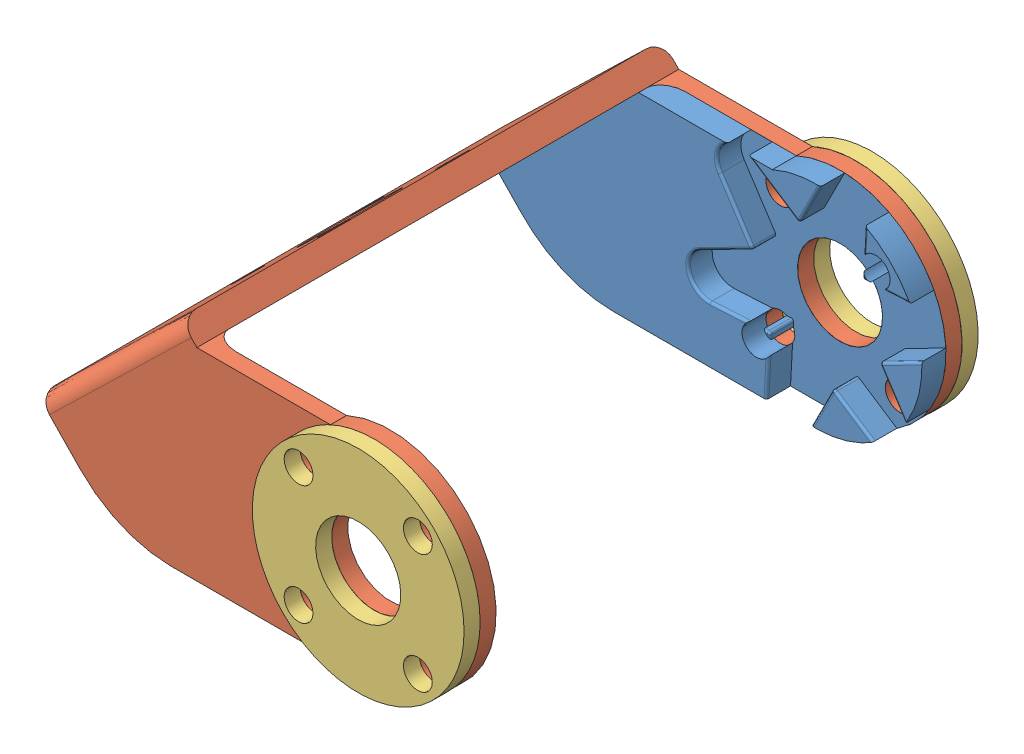
SolidWorks assembly box0_right_supplement, configuration Predeterminado. Lengths in mm.
Overall size (61.37 37.28 64).
5 component instances, 3 part files, 10 mates.
Components (placement in the parent):
- supplement_right_offset_f_horn-1: supplement_right_offset_f_horn [Predeterminado] at (-9.6116 -34.4342 -15.8226) x (0.994321 -0.106425 0) z (-0.106425 -0.994321 0) size (52.15 3.04 29.06)
- box0-1: box0 [Predeterminado] at (-23.9788 -47.6142 42.1774) size (57.24 34.69 60)
  - offset_bracket-1: offset_bracket [Predeterminado] at (1.7542 14.53 -60) x (0.994321 -0.106425 0) z (-0.106425 -0.994321 0) size (54.46 60 29.06)
- suplement_external_bracket-1: suplement_external_bracket [Predeterminado] at (-9.6116 -34.4342 44.1774) x (0.707107 -0.707107 0) z (0.707107 0.707107 0) size (26.36 2 26.36)
- suplement_external_bracket-2: suplement_external_bracket [Predeterminado] at (-9.6116 -34.4342 -17.8226) x (0.707107 0.707107 0) z (-0.707107 0.707107 0) size (26.36 2 26.36)
Mates (geometry in assembly coordinates):
- Coincidente1: coincident: plane of supplement_right_offset_f_horn-1 through (-9.6116 -34.4342 -15.8226) normal (0 0 -1); line of box0-1/offset_bracket-1 through (-15.0626 -22.4342 -15.8226) axis (-1 0 0)
- Coincidente2: coincident anti-aligned: plane of supplement_right_offset_f_horn-1 through (-9.6116 -34.4342 -15.8226) normal (0 0 -1); plane of box0-1/offset_bracket-1 through (-34.8376 -31.7342 -15.8226) normal (0 0 1)
- Coincidente3: coincident anti-aligned: circle of supplement_right_offset_f_horn-1; cylinder of box0-1/offset_bracket-1 through (-9.6116 -34.4342 -15.8226) axis (0 0 -1) radius 5.3
- Coincidente4: coincident aligned: plane of box0-1/offset_bracket-1 through (-34.8376 -47.6142 -15.8226) normal (0 -1 0); plane of supplement_right_offset_f_horn-1 through (-9.6116 -47.6142 -12.8226) normal (0 -1 0)
- Concéntrica1: concentric: cylinder of box0-1/offset_bracket-1 through (-9.6116 -34.4342 40.1774) axis (0 0 1) radius 5.3; cylinder of suplement_external_bracket-1 through (-9.6116 -34.4342 42.1774) axis (0 0 1) radius 5.3
- Coincidente5: coincident: plane of box0-1/offset_bracket-1 through (-33.0918 -20.9991 42.1774) normal (0 0 1); plane of suplement_external_bracket-1 through (-9.6116 -34.4342 42.1774) normal (0 0 -1)
- Concéntrica2: concentric anti-aligned: cylinder of box0-1/offset_bracket-1 through (-17.0363 -27.0096 40.1774) axis (0 0 1) radius 1.8; cylinder of suplement_external_bracket-1 through (-17.0363 -27.0096 44.1774) axis (0 0 -1) radius 1.8
- Concéntrica3: concentric: cylinder of box0-1/offset_bracket-1 through (-9.6116 -34.4342 -15.8226) axis (0 0 -1) radius 5.3; cylinder of suplement_external_bracket-2 through (-9.6116 -34.4342 -19.8226) axis (0 0 1) radius 5.3
- Concéntrica4: concentric: cylinder of box0-1/offset_bracket-1 through (-2.187 -41.8588 -17.8226) axis (0 0 1) radius 1.8; cylinder of suplement_external_bracket-2 through (-2.187 -41.8588 -17.8226) axis (0 0 -1) radius 1.8
- Coincidente6: coincident anti-aligned: plane of box0-1/offset_bracket-1 through (-34.8376 -31.7342 -17.8226) normal (0 0 -1); plane of suplement_external_bracket-2 through (-9.6116 -34.4342 -17.8226) normal (0 0 1)
